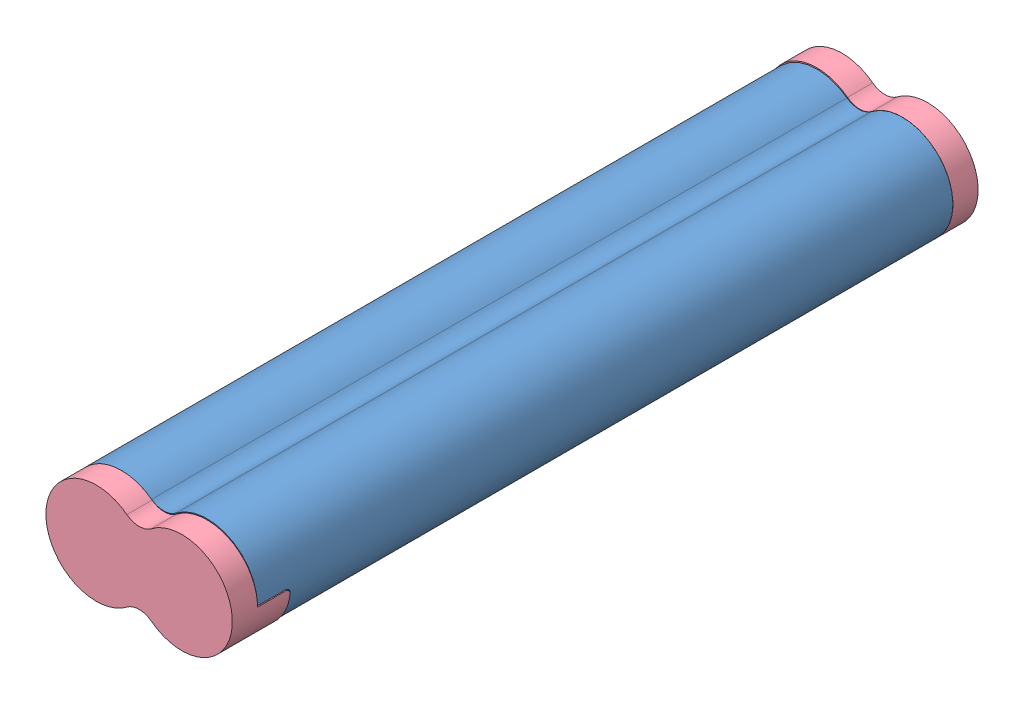
SolidWorks assembly Lead Case assembly, configuration Default. Lengths in mm.
Overall size (18.5 10.11 74).
9 component instances, 4 part files, 10 mates.
Components (placement in the parent):
- Main Caseing-1: Main Caseing [Default] at (24.3031 37.1408 52.9603) size (18.5 10.11 69)
- eraser-1: eraser [Default] at (24.3031 37.1408 75.2298) x (-0.477893 0.878418 0) z (0 0 -1) size (5.25 5.25 9.5)
- eraser-2: eraser [Default] at (24.3031 37.1408 49.0071) x (0.998608 -0.052749 0) z (0 0 1) size (5.25 5.25 9.5)
- eraser-3: eraser [Default] at (24.3031 37.1408 33.6553) x (0.994422 0.105479 0) z (0 0 1) size (5.25 5.25 9.5)
- Lead for case-1: Lead for case [Default] at (36.3136 35.0148 28.3334) size (0.07 0.07 55.9)
- Lead for case-2: Lead for case [Default] at (35.1609 33.8196 31.0371) size (0.07 0.07 55.9)
- Lead for case-3: Lead for case [Default] at (35.3408 33.9506 20.3406) x (0.92025 -0.391332 0) z (0 0 1) size (0.07 0.07 55.9)
- Lid for Casing-2: Lid for Casing [Default] at (24.3031 37.1408 89.9603) x (1 0 0) z (0 0 -1) size (18.5 10 7.38)
- Lid for Casing-3: Lid for Casing [Default] at (32.8031 37.2469 15.9603) x (-1 0 0) z (0 0 1) size (18.5 10 7.38)
Mates (geometry in assembly coordinates):
- Coincident1: coincident anti-aligned: circle of Main Caseing-1; circle of Lid for Casing-3
- Coincident2: coincident anti-aligned: circle of Main Caseing-1; circle of Lid for Casing-2
- Tangent3: tangent anti-aligned: cylinder of Main Caseing-1 through (32.8031 37.2469 18.4603) axis (0 0 1) radius 4.125; cylinder of Lead for case-3 through (35.3408 33.9506 76.2406) axis (0 0 -1) radius 0.035
- Tangent4: tangent anti-aligned: cylinder of Main Caseing-1 through (32.8031 37.2469 18.4603) axis (0 0 1) radius 4.125; cylinder of Lead for case-1 through (36.3136 35.0148 84.2334) axis (0 0 -1) radius 0.035
- Tangent5: tangent anti-aligned: cylinder of Main Caseing-1 through (32.8031 37.2469 18.4603) axis (0 0 1) radius 4.125; cylinder of Lead for case-2 through (35.1609 33.8196 86.9371) axis (0 0 -1) radius 0.035
- Concentric2: concentric aligned: cylinder of Main Caseing-1 through (24.3031 37.1408 18.4603) axis (0 0 1) radius 4.125; cylinder of eraser-1 through (24.3031 37.1408 65.7298) axis (0 0 1) radius 2.625
- Concentric3: concentric anti-aligned: cylinder of Main Caseing-1 through (24.3031 37.1408 18.4603) axis (0 0 1) radius 4.125; cylinder of eraser-3 through (24.3031 37.1408 43.1553) axis (0 0 -1) radius 2.625
- Concentric4: concentric anti-aligned: cylinder of Main Caseing-1 through (24.3031 37.1408 18.4603) axis (0 0 1) radius 4.125; cylinder of eraser-2 through (24.3031 37.1408 58.5071) axis (0 0 -1) radius 2.625
- Angle3: planar angle = 0 rad anti-aligned: plane of Lid for Casing-3 through (19.3031 37.2469 18.4603) normal (0 1 0); plane of Main Caseing-1 through (20.0035 37.0784 21.7103) normal (0 -1 0)
- Angle4: planar angle = 0 rad anti-aligned: plane of Lid for Casing-2 through (37.8031 37.1408 87.4603) normal (0 1 0); plane of Main Caseing-1 through (37.8031 37.2469 84.2103) normal (0 -1 0)
